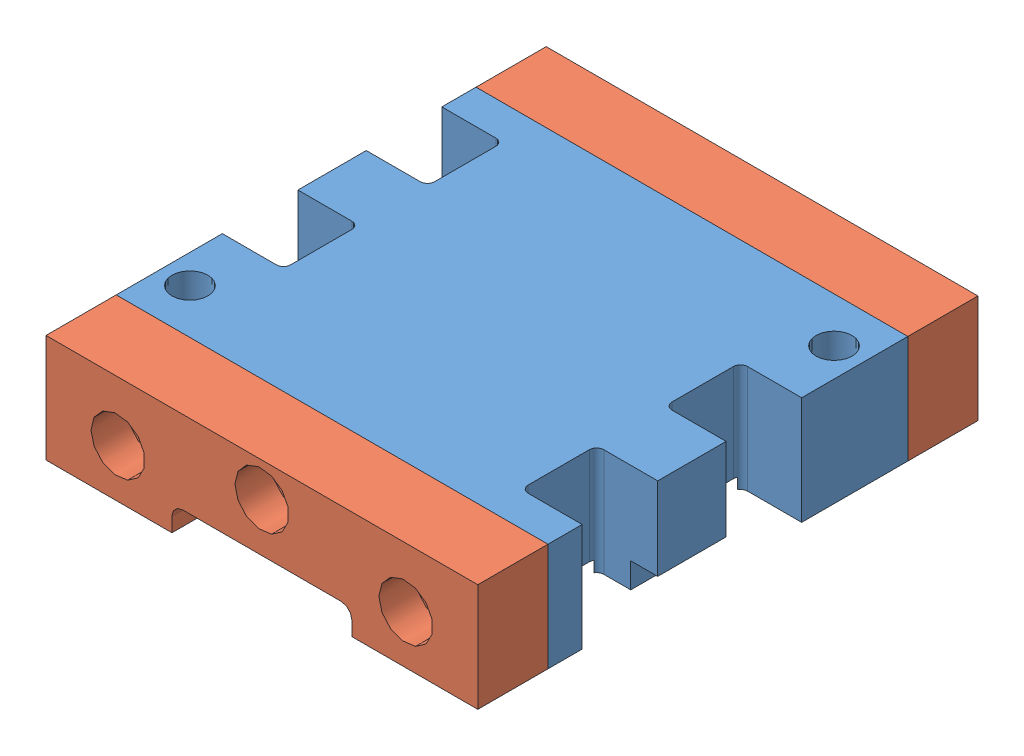
SolidWorks assembly Сборка2, configuration По умолчанию. Lengths in mm.
Overall size (120 30 139).
3 component instances, 2 part files, 6 mates.
Components (placement in the parent):
- Пуансон-2: Пуансон [Default] at (84.7865 149.5092 243.5787) size (120 30 100)
- Боковина пуансона-3: Боковина пуансона [Default] at (84.7865 164.5092 193.5787) x (1 0 0) z (0 0 -1) size (120 30 19.5)
- Боковина пуансона-4: Боковина пуансона [Default] at (84.7865 164.5092 293.5787) x (-1 0 0) z (0 0 1) size (120 30 19.5)
Mates (geometry in assembly coordinates):
- Совпадение1: coincident anti-aligned: plane of Пуансон-2 through (144.7865 179.5092 293.5787) normal (0 0 1); plane of Боковина пуансона-4 through (84.7865 164.5092 293.5787) normal (0 0 -1)
- Совпадение2: coincident anti-aligned: plane of Пуансон-2 through (144.7865 179.5092 193.5787) normal (0 0 -1); plane of Боковина пуансона-3 through (84.7865 164.5092 193.5787) normal (0 0 1)
- Концентричный1: concentric anti-aligned: cylinder of Пуансон-2 through (44.7865 163.0092 193.5787) axis (0 0 -1) radius 3.5; cylinder of Боковина пуансона-3 through (44.7865 163.0092 174.0787) axis (0 0 1) radius 4.5
- Концентричный2: concentric anti-aligned: cylinder of Пуансон-2 through (124.7865 163.0092 193.5787) axis (0 0 -1) radius 3.5; cylinder of Боковина пуансона-3 through (124.7865 163.0092 174.0787) axis (0 0 1) radius 4.5
- Концентричный3: concentric anti-aligned: cylinder of Пуансон-2 through (44.7865 163.0092 293.5787) axis (0 0 1) radius 3.5; cylinder of Боковина пуансона-4 through (44.7865 163.0092 313.0787) axis (0 0 -1) radius 4.5
- Концентричный4: concentric anti-aligned: cylinder of Пуансон-2 through (124.7865 163.0092 293.5787) axis (0 0 1) radius 3.5; cylinder of Боковина пуансона-4 through (124.7865 163.0092 313.0787) axis (0 0 -1) radius 4.5
